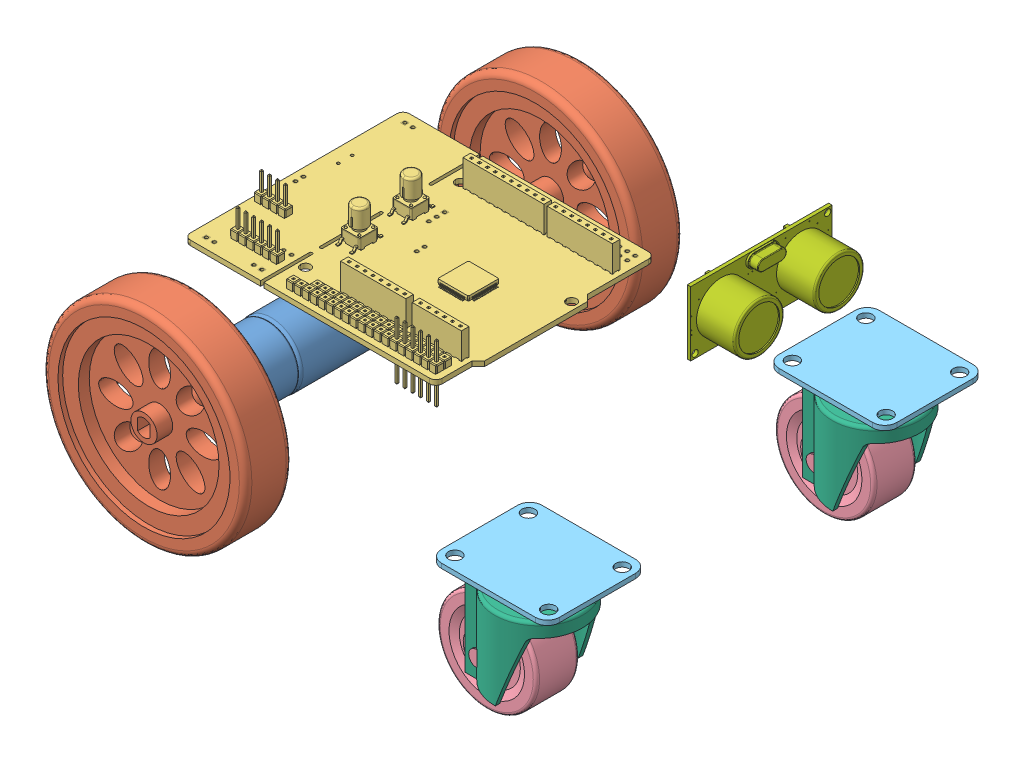
SolidWorks assembly Main Assy, configuration Default. Lengths in mm.
Overall size (172.02 111.6 140).
16 component instances, 7 part files, 12 mates.
Components (placement in the parent):
- Motor Thin Wheel Assembly-1: Motor Thin Wheel Assembly [Default] at (82.6548 42.3679 -42.2031) x (0 0 -1) z (1 0 0) size (69.19 65 65)
  - DC Motor-1: DC Motor [Default] at origin size (57.5 20.4 20.4)
  - 3763 Thin Wheel-1: 3763 Thin Wheel [Default] at (57.2938 0 0) x (0 0 -1) z (1 0 0) size (65 65 18.85)
- Motor Thin Wheel Assembly-2: Motor Thin Wheel Assembly [Default] at (82.6548 42.3679 -31.7906) x (0 0 1) z (-1 0 0) size (69.19 65 65)
  - DC Motor-1: DC Motor [Default] at origin size (57.5 20.4 20.4)
  - 3763 Thin Wheel-1: 3763 Thin Wheel [Default] at (57.2938 0 0) x (0 0 -1) z (1 0 0) size (65 65 18.85)
- NUCLEO-F401RE-1: NUCLEO-F401RE [Default] at (101.7602 65.219 -36.9968) x (0 0 -1) z (1 0 0) size (70 20.7 83.95)
- Caster-1: Caster [Default] at (215.5886 5.8982 -13.681) x (-1 0 0) z (0 0 -1) size (44.42 42.6 32.1)
  - Caster Wheel-3: Caster Wheel [Default] at (32.504 19.8447 -30.6341) x (0 1 0) z (0 0 1) size (31.75 31.75 20.3)
  - Caster Base-1: Caster Base [Default] at (22.804 45.0697 -30.6341) x (-1 0 0) z (0 0 -1) size (37.7 4 32.1)
  - Caster Body-1: Caster Body [Default] at (22.804 13.5697 -30.6341) x (-1 0 0) z (0 0 -1) size (28 26 28)
- HC-SR04 Ultrasonic Sensor-1: HC-SR04 Ultrasonic Sensor [Detailed] at (208.9758 111.1694 -36.9968) x (0 0 -1) z (0 -1 0) size (45.2 18.55 25.75)
- Caster-2: Caster [Default] at (215.5886 5.8982 -121.581) x (-1 0 0) z (0 0 -1) size (44.42 42.6 32.1)
  - Caster Wheel-3: Caster Wheel [Default] at (32.504 19.8447 -30.6341) x (0 1 0) z (0 0 1) size (31.75 31.75 20.3)
  - Caster Base-1: Caster Base [Default] at (22.804 45.0697 -30.6341) x (-1 0 0) z (0 0 -1) size (37.7 4 32.1)
  - Caster Body-1: Caster Body [Default] at (22.804 13.5697 -30.6341) x (-1 0 0) z (0 0 -1) size (28 26 28)
Mates (geometry in assembly coordinates):
- Concentric1: concentric anti-aligned: cylinder of Motor Thin Wheel Assembly-1/DC Motor-1 through (82.6548 42.3679 -84.3031) axis (0 0 1) radius 10; cylinder of Motor Thin Wheel Assembly-2/DC Motor-1 through (82.6548 42.3679 10.3094) axis (0 0 -1) radius 10
- Distance1: distance = 140 mm anti-aligned: plane of Motor Thin Wheel Assembly-2/3763 Thin Wheel-1 through (82.6548 42.3679 33.0032) normal (0 0 1); plane of Motor Thin Wheel Assembly-1/3763 Thin Wheel-1 through (82.6548 42.3679 -106.9968) normal (0 0 -1)
- Width1: width anti-aligned: plane of NUCLEO-F401RE-1 through (62.5102 66.799 -1.9968) normal (0 0 1); plane of NUCLEO-F401RE-1 through (84.9702 66.799 -71.9968) normal (0 0 -1); plane of Motor Thin Wheel Assembly-1/3763 Thin Wheel-1 through (82.6548 42.3679 -106.9968) normal (0 0 -1); plane of Motor Thin Wheel Assembly-2/3763 Thin Wheel-1 through (82.6548 42.3679 33.0032) normal (0 0 1)
- Coincident1: coincident aligned: plane of Motor Thin Wheel Assembly-1 through (82.6548 9.8679 -42.2031) normal (0 -1 0); plane of Caster Wheel-1 through (158.0451 9.8679 -36.9968) normal (0 -1 0)
- Width2: width aligned: plane of Caster Wheel-1 through (158.0451 32.4929 -29.3468) normal (0 0 1); plane of Motor Thin Wheel Assembly-2/3763 Thin Wheel-1 through (158.0451 32.4929 -44.6468) normal (0 0 -1); plane of Caster Wheel-1 through (82.6548 42.3679 33.0032) normal (0 0 1); plane of Motor Thin Wheel Assembly-1/3763 Thin Wheel-1 through (82.6548 42.3679 -106.9968) normal (0 0 -1)
- Tangent1: tangent aligned: cylinder of Motor Thin Wheel Assembly-2/3763 Thin Wheel-1 through (82.6548 42.3679 33.0032) axis (0 0 -1) radius 32.5; plane of Caster-1/Caster Wheel-3 through (183.0846 9.8679 16.9532) normal (0 -1 0)
- Parallel1: parallel aligned: plane of Caster-1/Caster Base-1 through (192.7846 52.4679 16.9532) normal (0 1 0)
- Width4: width anti-aligned: plane of HC-SR04 Ultrasonic Sensor-1 through (210.0758 100.8694 -14.3968) normal (0 0 1); plane of HC-SR04 Ultrasonic Sensor-1 through (210.0758 100.8694 -59.5968) normal (0 0 -1); plane of Motor Thin Wheel Assembly-1/3763 Thin Wheel-1 through (82.6548 42.3679 -106.9968) normal (0 0 -1); plane of Motor Thin Wheel Assembly-2/3763 Thin Wheel-1 through (82.6548 42.3679 33.0032) normal (0 0 1)
- Coincident4: coincident aligned: plane of Motor Thin Wheel Assembly-2/3763 Thin Wheel-1 through (82.6548 42.3679 33.0032) normal (0 0 1); plane of Caster-1/Caster Base-1 through (173.9346 52.4679 33.0032) normal (0 0 1)
- Coincident5: coincident aligned: plane of Motor Thin Wheel Assembly-1 through (82.6548 9.8679 -42.2031) normal (0 -1 0); plane of Caster-2/Caster Wheel-3 through (183.0846 9.8679 -90.9468) normal (0 -1 0)
- Coincident6: coincident: plane of Motor Thin Wheel Assembly-1/3763 Thin Wheel-1 through (82.6548 42.3679 -106.9968) normal (0 0 -1); line of Caster-2/Caster Base-1 through (207.7846 52.4679 -106.9968) axis (-1 0 0)
- Coincident7: coincident aligned: plane of Caster-1/Caster Base-1 through (211.6346 52.4679 0.9032) normal (1 0 0); plane of Caster-2/Caster Base-1 through (211.6346 52.4679 -106.9968) normal (1 0 0)
